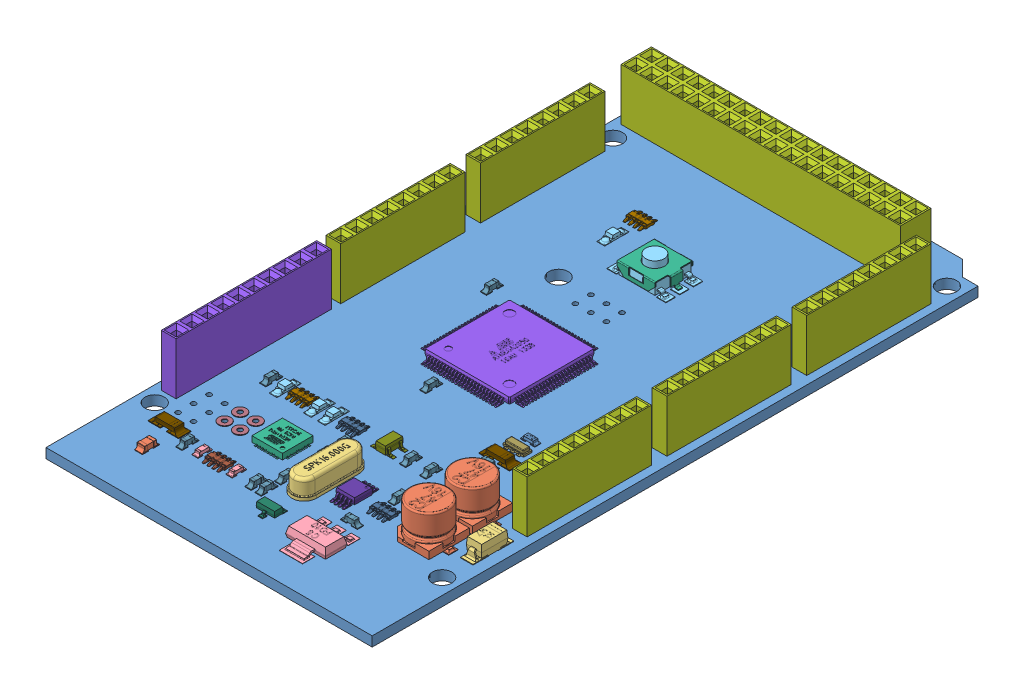
SolidWorks assembly User Library-arduino_MEGA2650-1, configuration Default. Lengths in mm.
Overall size (53.34 10.51 101.6).
53 component instances, 26 part files, 0 mates.
Components (placement in the parent):
- User Library-arduino_MEGA2650-1_MEGAboard-1: User Library-arduino_MEGA2650-1_MEGAboard [Default] at origin size (53.34 1.6 101.6)
- User Library-arduino_MEGA2650-1_47uf CAP Dcase-1: User Library-arduino_MEGA2650-1_47uf CAP Dcase [Default] at (-9.144 0 -18.415) x (0 0 -1) z (1 0 0) size (6.6 5.81 8)
- User Library-arduino_MEGA2650-1_47uf CAP Dcase-2: User Library-arduino_MEGA2650-1_47uf CAP Dcase [Default] at (-9.144 0 -25.527) x (0 0 -1) z (1 0 0) size (6.6 5.81 8)
- User Library-arduino_MEGA2650-1_crystal-1: User Library-arduino_MEGA2650-1_crystal [Default] at (-26.035 0 -18.415) x (1 0 0) z (0 0 -1) size (4 5 11)
- User Library-arduino_MEGA2650-1_reg-1: User Library-arduino_MEGA2650-1_reg [Default] at (-17.78 0 -8.636) size (6.5 1.69 8.3)
- User Library-arduino_MEGA2650-1_led-1: User Library-arduino_MEGA2650-1_led [Default] at (-34.29 0 -27.94) x (0 0 1) z (-1 0 0) size (4.01 0.9 1.55)
- User Library-arduino_MEGA2650-1_atmega16u2-1: User Library-arduino_MEGA2650-1_atmega16u2 [Default] at (-34.671 0.06 -20) x (1 0 0) z (0 0 -1) size (5.5 1.01 5.5)
- User Library-arduino_MEGA2650-1_led-2: User Library-arduino_MEGA2650-1_led [Default] at (-36.576 0 -27.94) x (0 0 -1) z (1 0 0) size (4.01 0.9 1.55)
- User Library-arduino_MEGA2650-1_led-3: User Library-arduino_MEGA2650-1_led [Default] at (-42.164 0 -27.94) x (0 0 1) z (-1 0 0) size (4.01 0.9 1.55)
- User Library-arduino_MEGA2650-1_led-4: User Library-arduino_MEGA2650-1_led [Default] at (-36.83 0 -76.2) x (0 0 1) z (-1 0 0) size (4.01 0.9 1.55)
- User Library-arduino_MEGA2650-1_8 PORT HEADER-1: User Library-arduino_MEGA2650-1_8 PORT HEADER [Default] at (-50.8 0 -45.72) x (0 0 -1) z (1 0 0) size (20.32 10.51 2.41)
- User Library-arduino_MEGA2650-1_8 PORT HEADER-2: User Library-arduino_MEGA2650-1_8 PORT HEADER [Default] at (-2.54 0 -27.94) x (0 0 -1) z (1 0 0) size (20.32 10.51 2.41)
- User Library-arduino_MEGA2650-1_8 PORT HEADER-3: User Library-arduino_MEGA2650-1_8 PORT HEADER [Default] at (-2.54 0 -50.8) x (0 0 -1) z (1 0 0) size (20.32 10.51 2.41)
- User Library-arduino_MEGA2650-1_10 PORT HEADER-1: User Library-arduino_MEGA2650-1_10 PORT HEADER [Default] at (-50.8 0 -18.796) x (0 0 -1) z (1 0 0) size (25.4 10.51 2.41)
- User Library-arduino_MEGA2650-1_102 RESISTOR PACK-1: User Library-arduino_MEGA2650-1_102 RESISTOR PACK [Default] at (-36.83 0 -80.645) size (3.2 0.52 3)
- User Library-arduino_MEGA2650-1_102 RESISTOR PACK-2: User Library-arduino_MEGA2650-1_102 RESISTOR PACK [Default] at (-39.37 0 -27.94) size (3.2 0.52 3)
- User Library-arduino_MEGA2650-1_103 RESISTOR PACK-1: User Library-arduino_MEGA2650-1_103 RESISTOR PACK [Default] at (-31.115 0 -27.94) size (3.2 0.52 3)
- User Library-arduino_MEGA2650-1_220 RESISTOR PACK-1: User Library-arduino_MEGA2650-1_220 RESISTOR PACK [Default] at (-37.084 0 -12.065) size (3.2 0.52 3)
- User Library-arduino_MEGA2650-1_16mhz crystal - measured-1: User Library-arduino_MEGA2650-1_16mhz crystal - measured [Default] at (-14.605 0 -38.354) size (3.4 0.8 2.01)
- User Library-arduino_MEGA2650-1_PADS001-1: User Library-arduino_MEGA2650-1_PADS001 [Default] at (-39.878 0.1 -18.288) x (-1 0 0) z (0 0 1) size (4.54 0.1 4.54)
- User Library-arduino_MEGA2650-1_603 cap on pad-1: User Library-arduino_MEGA2650-1_603 cap on pad [Default] at (-44.45 0 -27.94) x (0 0 -1) z (1 0 0) size (2.76 0.9 1.02)
- User Library-arduino_MEGA2650-1_ssot3-1: User Library-arduino_MEGA2650-1_ssot3 [Default] at (-25.908 0 -9.144) x (-1 0 0) z (0 0 -1) size (3 1.13 3.09)
- User Library-arduino_MEGA2650-1_603 cap on pad-2: User Library-arduino_MEGA2650-1_603 cap on pad [Default] at (-29.337 0 -24.765) x (0 0 1) z (-1 0 0) size (2.76 0.9 1.02)
- User Library-arduino_MEGA2650-1_603 cap on pad-3: User Library-arduino_MEGA2650-1_603 cap on pad [Default] at (-30.988 0 -12.065) x (0 0 -1) z (1 0 0) size (2.76 0.9 1.02)
- User Library-arduino_MEGA2650-1_lmv358-1: User Library-arduino_MEGA2650-1_lmv358 [Default] at (-25.146 0 -27.94) size (3.7 1.4 2.9)
- User Library-arduino_MEGA2650-1_603 cap on pad-4: User Library-arduino_MEGA2650-1_603 cap on pad [Default] at (-17.653 0 -14.351) size (2.76 0.9 1.02)
- User Library-arduino_MEGA2650-1_603 cap on pad-5: User Library-arduino_MEGA2650-1_603 cap on pad [Default] at (-29.337 0 -12.065) x (0 0 1) z (-1 0 0) size (2.76 0.9 1.02)
- User Library-arduino_MEGA2650-1_603 cap on pad-6: User Library-arduino_MEGA2650-1_603 cap on pad [Default] at (-29.337 0 -21.59) x (0 0 1) z (-1 0 0) size (2.76 0.9 1.02)
- User Library-arduino_MEGA2650-1_603 cap on pad-7: User Library-arduino_MEGA2650-1_603 cap on pad [Default] at (-29.337 0 -15.24) x (0 0 1) z (-1 0 0) size (2.76 0.9 1.02)
- User Library-arduino_MEGA2650-1_603 cap on pad-8: User Library-arduino_MEGA2650-1_603 cap on pad [Default] at (-42.291 0 -12.065) x (0 0 1) z (-1 0 0) size (2.76 0.9 1.02)
- User Library-arduino_MEGA2650-1_lp2985dgkr-1: User Library-arduino_MEGA2650-1_lp2985dgkr [Default] at (-21.336 0 -18.415) x (0 0 -1) z (1 0 0) size (5.85 1.1 3)
- User Library-arduino_MEGA2650-1_cd1206 diode-1: User Library-arduino_MEGA2650-1_cd1206 diode [Default] at (-14.605 0 -35.56) x (0 0 1) z (-1 0 0) size (2.08 0.96 5)
- User Library-arduino_MEGA2650-1_cd1206 diode-2: User Library-arduino_MEGA2650-1_cd1206 diode [Default] at (-46.228 0 -13.081) x (0 0 1) z (-1 0 0) size (2.08 0.96 5)
- User Library-arduino_MEGA2650-1_603 resistor-1: User Library-arduino_MEGA2650-1_603 resistor [Default] at (-29.337 0 -18.415) x (0 0 1) z (-1 0 0) size (2.36 0.62 1.03)
- User Library-arduino_MEGA2650-1_blm21-1: User Library-arduino_MEGA2650-1_blm21 [Default] at (-45.085 0 -8.255) x (0 0 -1) z (1 0 0) size (2.78 0.95 1.32)
- User Library-arduino_MEGA2650-1_m7 diode-1: User Library-arduino_MEGA2650-1_m7 diode [Default] at (-2.794 0 -21.59) x (0 0 -1) z (1 0 0) size (6.66 2.35 2.5)
- User Library-arduino_MEGA2650-1_MLC0603-1: User Library-arduino_MEGA2650-1_MLC0603 [Default] at (-34.29 0 -12.065) x (0 0 -1) z (1 0 0) size (2.36 0.6 1.03)
- User Library-arduino_MEGA2650-1_MLC0603-2: User Library-arduino_MEGA2650-1_MLC0603 [Default] at (-39.878 0 -12.065) x (0 0 -1) z (1 0 0) size (2.36 0.6 1.03)
- User Library-arduino_MEGA2650-1_RESET CORE-1: User Library-arduino_MEGA2650-1_RESET CORE [Default] at (-27.94 0.1 -74.168) x (0 0 1) z (-1 0 0) size (6.2 3.1 9.6)
- User Library-arduino_MEGA2650-1_RESET-1: User Library-arduino_MEGA2650-1_RESET [Default] at (-27.94 0.1 -74.168) size (7.3 2 6.2)
- User Library-arduino_MEGA2650-1_8 PORT HEADER-4: User Library-arduino_MEGA2650-1_8 PORT HEADER [Default] at (-2.54 0 -73.66) x (0 0 -1) z (1 0 0) size (20.32 10.51 2.41)
- User Library-arduino_MEGA2650-1_8 PORT HEADER-5: User Library-arduino_MEGA2650-1_8 PORT HEADER [Default] at (-50.8 0 -68.58) x (0 0 -1) z (1 0 0) size (20.32 10.51 2.41)
- User Library-arduino_MEGA2650-1_603 cap on pad-9: User Library-arduino_MEGA2650-1_603 cap on pad [Default] at (-21.59 0 -27.94) x (0 0 1) z (-1 0 0) size (2.76 0.9 1.02)
- User Library-arduino_MEGA2650-1_603 cap on pad-10: User Library-arduino_MEGA2650-1_603 cap on pad [Default] at (-18.288 0 -27.94) x (0 0 1) z (-1 0 0) size (2.76 0.9 1.02)
- User Library-arduino_MEGA2650-1_103 RESISTOR PACK-2: User Library-arduino_MEGA2650-1_103 RESISTOR PACK [Default] at (-16.51 0 -18.415) size (3.2 0.52 3)
- User Library-arduino_MEGA2650-1_603 cap on pad-11: User Library-arduino_MEGA2650-1_603 cap on pad [Default] at (-17.145 0 -21.59) x (0 0 -1) z (1 0 0) size (2.76 0.9 1.02)
- User Library-arduino_MEGA2650-1_603 cap on pad-12: User Library-arduino_MEGA2650-1_603 cap on pad [Default] at (-39.37 0 -58.928) x (0 0 1) z (-1 0 0) size (2.76 0.9 1.02)
- User Library-arduino_MEGA2650-1_603 cap on pad-13: User Library-arduino_MEGA2650-1_603 cap on pad [Default] at (-14.605 0 -33.528) size (2.76 0.9 1.02)
- User Library-arduino_MEGA2650-1_603 resistor-2: User Library-arduino_MEGA2650-1_603 resistor [Default] at (-14.605 0 -40.513) x (-1 0 0) z (0 0 -1) size (2.36 0.62 1.03)
- User Library-arduino_MEGA2650-1_603 cap on pad-14: User Library-arduino_MEGA2650-1_603 cap on pad [Default] at (-7.112 0 -38.608) x (0 0 1) z (-1 0 0) size (2.76 0.9 1.02)
- User Library-arduino_MEGA2650-1_603 cap on pad-15: User Library-arduino_MEGA2650-1_603 cap on pad [Default] at (-30.4038 0 -40.0558) x (0 0 1) z (-1 0 0) size (2.76 0.9 1.02)
- User Library-arduino_MEGA2650-1_18 X 2 ROW HEADER-1: User Library-arduino_MEGA2650-1_18 X 2 ROW HEADER [Default] at (-50.8 0 -95.25) size (45.72 10.51 4.95)
- User Library-arduino_MEGA2650-1_atmega2650-16AU-1: User Library-arduino_MEGA2650-1_atmega2650-16AU [Default] at (-28.3464 0.1 -50.8) x (0 0 1) z (-1 0 0) size (16.81 1.11 16.81)
